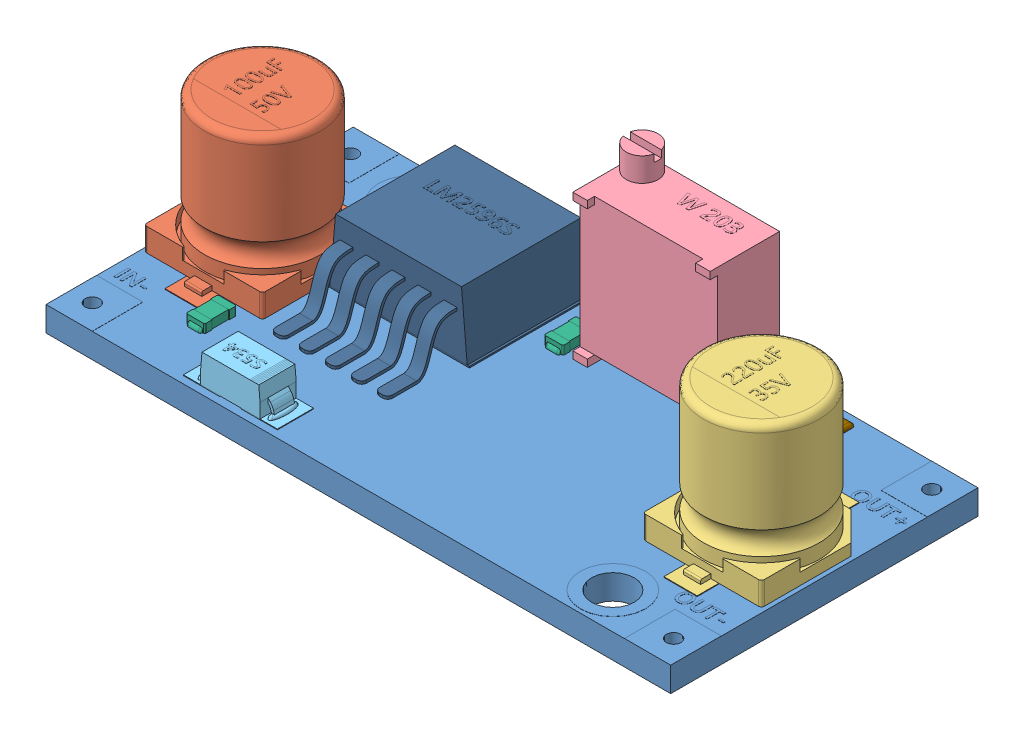
SolidWorks assembly LM2596 DC to DC Buck Converter 3 A, configuration Default. Lengths in mm.
Overall size (43.2 15.15 21.25).
11 component instances, 10 part files, 0 mates.
Components (placement in the parent):
- lm2596board-1: lm2596board [Default] at origin size (43.2 1.71 21.25)
- smd100uF-1: smd100uF [Default] at (-17.25 2.55 0) x (0 0 -1) z (1 0 0) size (11.2 9.76 8.2)
- smd220uF-1: smd220uF [Default] at (17.25 2.55 0) x (0 0 -1) z (1 0 0) size (11.2 9.76 8.2)
- TrimmerW203-1: TrimmerW203 [Default] at (4.6271 6.95 -9.1276) size (9.5 15.15 4.8)
- smdS537diode-1: smdS537diode [Default] at (-9.35 1.75 8.875) x (-1 0 0) z (0 0 -1) size (6.5 2.13 2.5)
- smdceramiccapacitor-1: smdceramiccapacitor [Default] at (-1.3196 1.7 -5.2916) x (0 0 1) z (-1 0 0) size (2.55 0.62 1.3)
- smdceramiccapacitor-2: smdceramiccapacitor [Default] at (-15 1.7 5.7969) x (0 0 1) z (-1 0 0) size (2.55 0.62 1.3)
- smdResistor331-1: smdResistor331 [Default] at (-1.2696 1.7 -8.4665) x (0 0 1) z (-1 0 0) size (2.54 0.62 1.34)
- smdResistor102-1: smdResistor102 [Default] at (10.7771 1.7 -8.4665) x (0 0 -1) z (1 0 0) size (2.54 0.62 1.34)
- smdLED-1: smdLED [Default] at (13.0521 1.75 -8.4701) x (0 0 -1) z (1 0 0) size (3.2 0.84 1.28)
- LM2596S-1: LM2596S [Default] at (-8.0627 1.8 -4.5407) size (9.8 4.61 14.95)
